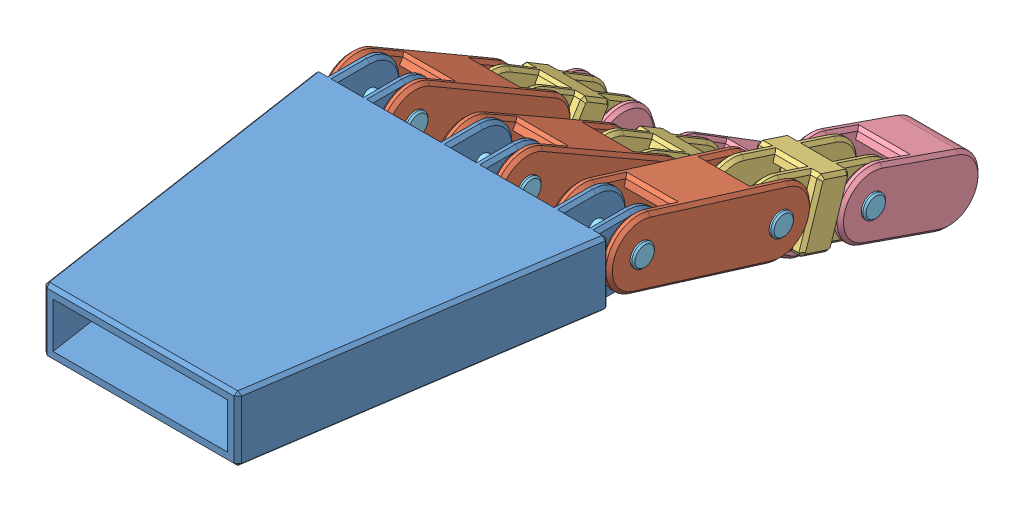
SolidWorks assembly Robot_Hand, configuration Default. Lengths in mm.
Overall size (92 98.18 218.4).
22 component instances, 5 part files, 12 mates.
Components (placement in the parent):
- hand_palm-1: hand_palm [Default] at origin size (89.72 20 120)
- Robot_Finger-1: Robot_Finger [Default] at (35 0 -10) x (0 0.295501 0.955343) z (-1 0 0) size (120.32 21.91 22) (flexible)
  - finger_inner-1: finger_inner [Default] at (-22.5 0 0) x (-1 0 0) z (0 0 -1) size (65 20 20)
  - finger_middle-1: finger_middle [Default] at (-59.9977 -0.2618 0) x (-0.999848 -0.017452 0) z (0 0 -1) size (50 20 20)
  - finger_top-1: finger_top [Default] at (-87.4878 -0.9598 0) x (-0.999391 -0.034899 0) z (0 0 -1) size (45 20 20)
  - finger_connector-1: finger_connector [Default] x (1 0 0) z (0 0 -1) size (7 7 22)
  - finger_connector-2: finger_connector [Default] at (-45 0 0) x (0.017452 -0.999848 0) z (0 0 -1) size (7 7 22)
  - finger_connector-3: finger_connector [Default] at (-74.9954 -0.5236 0) x (-0.999391 -0.034899 0) z (0 0 -1) size (7 7 22)
- Robot_Finger-2: Robot_Finger [Default] at (0 0 -10) x (0 0.497306 0.867575) z (-1 0 0) size (120.32 21.91 22) (flexible)
  - finger_inner-1: finger_inner [Default] at (-22.5 0 0) x (-1 0 0) z (0 0 -1) size (65 20 20)
  - finger_middle-1: finger_middle [Default] at (-59.9977 -0.2618 0) x (-0.999848 -0.017452 0) z (0 0 -1) size (50 20 20)
  - finger_top-1: finger_top [Default] at (-87.4878 -0.9598 0) x (-0.999391 -0.034899 0) z (0 0 -1) size (45 20 20)
  - finger_connector-1: finger_connector [Default] x (1 0 0) z (0 0 -1) size (7 7 22)
  - finger_connector-2: finger_connector [Default] at (-45 0 0) x (0.017452 -0.999848 0) z (0 0 -1) size (7 7 22)
  - finger_connector-3: finger_connector [Default] at (-74.9954 -0.5236 0) x (-0.999391 -0.034899 0) z (0 0 -1) size (7 7 22)
- Robot_Finger-3: Robot_Finger [Default] at (-35 0 -10) x (0 0.502982 0.864297) z (-1 0 0) size (117.51 45.21 22) (flexible)
  - finger_inner-1: finger_inner [Default] at (-22.5 0 0) x (-1 0 0) z (0 0 -1) size (65 20 20)
  - finger_middle-1: finger_middle [Default] at (-59.9977 -0.2618 0) x (-0.999848 -0.017452 0) z (0 0 -1) size (50 20 20)
  - finger_top-1: finger_top [Default] at (-84.1855 -8.9967 0) x (-0.735202 -0.677848 0) z (0 0 -1) size (45 20 20)
  - finger_connector-1: finger_connector [Default] x (1 0 0) z (0 0 -1) size (7 7 22)
  - finger_connector-2: finger_connector [Default] at (-45 0 0) x (0.017452 -0.999848 0) z (0 0 -1) size (7 7 22)
  - finger_connector-3: finger_connector [Default] at (-74.9954 -0.5236 0) x (-0.735202 -0.677848 0) z (0 0 -1) size (7 7 22)
Mates (geometry in assembly coordinates):
- Coincident1: coincident aligned: plane of hand_palm-1 through (0 0 0) normal (0 0 1); plane of assembly through (0 0 0) normal (0 0 1)
- Coincident2: coincident aligned: plane of hand_palm-1 through (0 0 0) normal (0 1 0); plane of assembly through (0 0 0) normal (0 1 0)
- Coincident3: coincident aligned: plane of hand_palm-1 through (0 0 0) normal (1 0 0); plane of assembly through (0 0 0) normal (1 0 0)
- Concentric1: concentric aligned: cylinder of hand_palm-1 through (42 0 -10) axis (-1 0 0) radius 2.5; cylinder of Robot_Finger-1/finger_connector-1 through (45 0 -10) axis (-1 0 0) radius 2.5
- Coincident5: coincident anti-aligned: plane of hand_palm-1 through (42 0 -10) normal (1 0 0); plane of Robot_Finger-1/finger_inner-1 through (42 0 -10) normal (-1 0 0)
- LimitAngle1: limit planar angle = 0.299979 rad aligned: plane of Robot_Finger-1; plane of assembly through (0 0 0) normal (0 0 1)
- Coincident7: coincident anti-aligned: circle of hand_palm-1; cylinder of Robot_Finger-2/finger_connector-1 through (10 0 -10) axis (-1 0 0) radius 2.5
- Coincident8: coincident anti-aligned: plane of hand_palm-1 through (-7 0 -10) normal (-1 0 0); plane of Robot_Finger-2/finger_inner-1 through (-7 0 -10) normal (1 0 0)
- LimitAngle2: limit planar angle = 0.520491 rad aligned: plane of Robot_Finger-2; plane of assembly through (0 0 0) normal (0 0 1)
- Concentric2: concentric aligned: cylinder of hand_palm-1 through (-28 0 -10) axis (-1 0 0) radius 2.5; cylinder of Robot_Finger-3/finger_connector-1 through (-25 0 -10) axis (-1 0 0) radius 2.5
- Coincident10: coincident anti-aligned: plane of hand_palm-1 through (-28 0 -10) normal (1 0 0); plane of Robot_Finger-3/finger_inner-1 through (-28 0 -10) normal (-1 0 0)
- LimitAngle3: limit planar angle = 0.527046 rad aligned: plane of Robot_Finger-3; plane of assembly through (0 0 0) normal (0 0 1)
